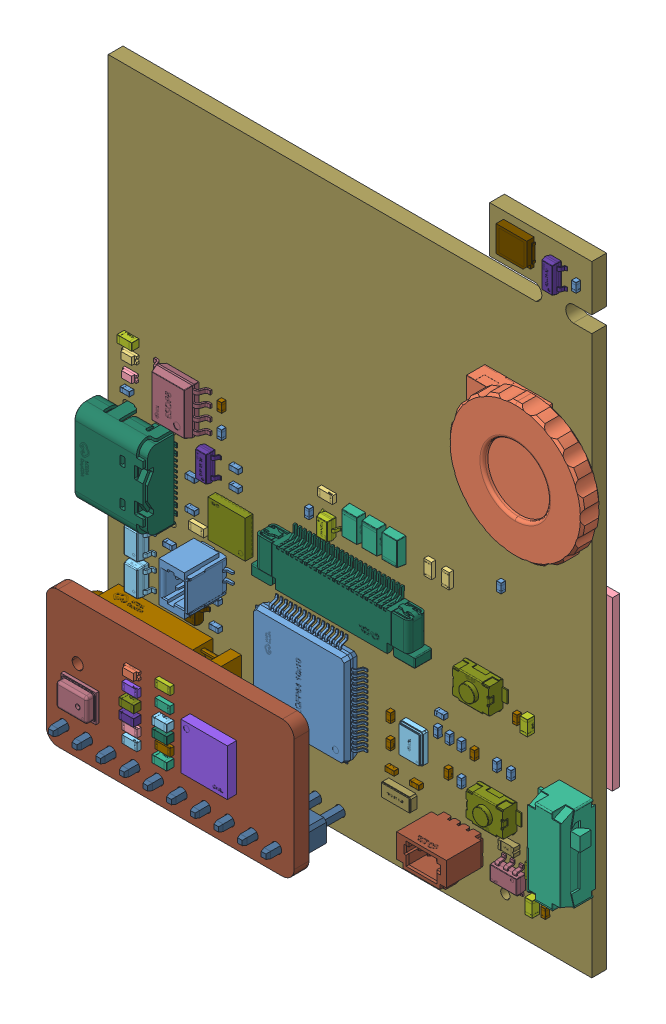
SolidWorks assembly acho_pcb, configuration 默认. Lengths in mm.
Overall size (56.46 68.19 13.11).
365 component instances, 66 part files, 0 mates.
Components (placement in the parent):
- acho_pcb.step-1: acho_pcb.step [默认] at origin size (55.33 67.76 13.11)
  - fs8s-R9.step-1: fs8s-R9.step [默认] at (9.271 25.4001 1.5862) size (1 0.5 0.5)
    - R0402.step-1: R0402.step [默认] at origin size (1 0.5 0.5)
      - SOLID.step-1: SOLID.step [默认] at origin size (1 0.5 0.5)
  - fs8s-R8.step-1: fs8s-R8.step [默认] at (9.271 22.352 1.5862) size (1 0.5 0.5)
    - R0402.step-1: R0402.step [默认] at origin size (1 0.5 0.5)
      - SOLID.step-1: SOLID.step [默认] at origin size (1 0.5 0.5)
  - fs8s-R3.step-1: fs8s-R3.step [默认] at (17.018 27.8131 0) x (-1 0 0) z (0 0 -1) size (1 0.5 0.5)
    - R0402.step-1: R0402.step [默认] at origin size (1 0.5 0.5)
      - SOLID.step-1: SOLID.step [默认] at origin size (1 0.5 0.5)
  - fs8s-R5.step-1: fs8s-R5.step [默认] at (21.463 27.8131 0) x (1 0 0) z (0 0 -1) size (1 0.5 0.5)
    - R0402.step-1: R0402.step [默认] at origin size (1 0.5 0.5)
      - SOLID.step-1: SOLID.step [默认] at origin size (1 0.5 0.5)
  - fs8s-R4.step-1: fs8s-R4.step [默认] at (19.304 27.8131 0) x (-1 0 0) z (0 0 -1) size (1 0.5 0.5)
    - R0402.step-1: R0402.step [默认] at origin size (1 0.5 0.5)
      - SOLID.step-1: SOLID.step [默认] at origin size (1 0.5 0.5)
  - fs8s-R13.step-1: fs8s-R13.step [默认] at (2.286 29.9721 1.5862) size (1 0.5 0.5)
    - R0402.step-1: R0402.step [默认] at origin size (1 0.5 0.5)
      - SOLID.step-1: SOLID.step [默认] at origin size (1 0.5 0.5)
  - fs8s-R16.step-1: fs8s-R16.step [默认] at (12.446 31.1151 1.5862) x (0 1 0) z (0 0 1) size (1 0.5 0.5)
    - R0402.step-1: R0402.step [默认] at origin size (1 0.5 0.5)
      - SOLID.step-1: SOLID.step [默认] at origin size (1 0.5 0.5)
  - fs8s-R28.step-1: fs8s-R28.step [默认] at (42.483 31.866 1.5862) x (0 -1 0) z (0 0 1) size (1 0.5 0.5)
    - R0402.step-1: R0402.step [默认] at origin size (1 0.5 0.5)
      - SOLID.step-1: SOLID.step [默认] at origin size (1 0.5 0.5)
  - fs8s-R26.step-1: fs8s-R26.step [默认] at (6.858 14.478 1.5862) x (-1 0 0) z (0 0 1) size (1 0.5 0.5)
    - R0402.step-1: R0402.step [默认] at origin size (1 0.5 0.5)
      - SOLID.step-1: SOLID.step [默认] at origin size (1 0.5 0.5)
  - fs8s-R31.step-1: fs8s-R31.step [默认] at (7.62 4.953 0) x (1 0 0) z (0 0 -1) size (1 0.5 0.5)
    - R0402.step-1: R0402.step [默认] at origin size (1 0.5 0.5)
      - SOLID.step-1: SOLID.step [默认] at origin size (1 0.5 0.5)
  - fs8s-R29.step-1: fs8s-R29.step [默认] at (11.43 9.652 0) x (0 1 0) z (0 0 -1) size (1 0.5 0.5)
    - R0402.step-1: R0402.step [默认] at origin size (1 0.5 0.5)
      - SOLID.step-1: SOLID.step [默认] at origin size (1 0.5 0.5)
  - fs8s-R32.step-1: fs8s-R32.step [默认] at (7.62 6.223 0) x (1 0 0) z (0 0 -1) size (1 0.5 0.5)
    - R0402.step-1: R0402.step [默认] at origin size (1 0.5 0.5)
      - SOLID.step-1: SOLID.step [默认] at origin size (1 0.5 0.5)
  - fs8s-R25.step-1: fs8s-R25.step [默认] at (6.858 17.907 1.5862) x (-1 0 0) z (0 0 1) size (1 0.5 0.5)
    - R0402.step-1: R0402.step [默认] at origin size (1 0.5 0.5)
      - SOLID.step-1: SOLID.step [默认] at origin size (1 0.5 0.5)
  - fs8s-R27.step-1: fs8s-R27.step [默认] at (6.858 12.827 1.5862) size (1 0.5 0.5)
    - R0402.step-1: R0402.step [默认] at origin size (1 0.5 0.5)
      - SOLID.step-1: SOLID.step [默认] at origin size (1 0.5 0.5)
  - fs8s-R7.step-1: fs8s-R7.step [默认] at (11.811 12.7 1.5862) x (-1 0 0) z (0 0 1) size (1 0.5 0.5)
    - R0402.step-1: R0402.step [默认] at origin size (1 0.5 0.5)
      - SOLID.step-1: SOLID.step [默认] at origin size (1 0.5 0.5)
  - fs8s-R10.step-1: fs8s-R10.step [默认] at (50.5461 63.8811 1.5862) x (0 1 0) z (0 0 1) size (1 0.5 0.5)
    - R0402.step-1: R0402.step [默认] at origin size (1 0.5 0.5)
      - SOLID.step-1: SOLID.step [默认] at origin size (1 0.5 0.5)
  - fs8s-R2.step-1: fs8s-R2.step [默认] at (38.2271 11.557 1.5862) x (0 1 0) z (0 0 1) size (1 0.5 0.5)
    - R0402.step-1: R0402.step [默认] at origin size (1 0.5 0.5)
      - SOLID.step-1: SOLID.step [默认] at origin size (1 0.5 0.5)
  - fs8s-R1.step-1: fs8s-R1.step [默认] at (24.257 10.795 0) x (0 1 0) z (0 0 -1) size (1 0.5 0.5)
    - R0402.step-1: R0402.step [默认] at origin size (1 0.5 0.5)
      - SOLID.step-1: SOLID.step [默认] at origin size (1 0.5 0.5)
  - fs8s-R30.step-1: fs8s-R30.step [默认] at (36.0681 16.764 1.5862) x (-1 0 0) z (0 0 1) size (1 0.5 0.5)
    - R0402.step-1: R0402.step [默认] at origin size (1 0.5 0.5)
      - SOLID.step-1: SOLID.step [默认] at origin size (1 0.5 0.5)
  - fs8s-R23.step-1: fs8s-R23.step [默认] at (21.844 28.4481 1.5862) x (0 1 0) z (0 0 1) size (1 0.5 0.5)
    - R0402.step-1: R0402.step [默认] at origin size (1 0.5 0.5)
      - SOLID.step-1: SOLID.step [默认] at origin size (1 0.5 0.5)
  - fs8s-R18.step-1: fs8s-R18.step [默认] at (43.5611 14.9627 1.5862) x (0 1 0) z (0 0 1) size (1 0.5 0.5)
    - R0402.step-1: R0402.step [默认] at origin size (1 0.5 0.5)
      - SOLID.step-1: SOLID.step [默认] at origin size (1 0.5 0.5)
  - fs8s-R22.step-1: fs8s-R22.step [默认] at (35.6871 14.986 1.5862) x (0 1 0) z (0 0 1) size (1 0.5 0.5)
    - R0402.step-1: R0402.step [默认] at origin size (1 0.5 0.5)
      - SOLID.step-1: SOLID.step [默认] at origin size (1 0.5 0.5)
  - fs8s-R19.step-1: fs8s-R19.step [默认] at (42.0371 14.986 1.5862) x (0 1 0) z (0 0 1) size (1 0.5 0.5)
    - R0402.step-1: R0402.step [默认] at origin size (1 0.5 0.5)
      - SOLID.step-1: SOLID.step [默认] at origin size (1 0.5 0.5)
  - fs8s-R20.step-1: fs8s-R20.step [默认] at (38.2271 14.986 1.5862) x (0 1 0) z (0 0 1) size (1 0.5 0.5)
    - R0402.step-1: R0402.step [默认] at origin size (1 0.5 0.5)
      - SOLID.step-1: SOLID.step [默认] at origin size (1 0.5 0.5)
  - fs8s-R21.step-1: fs8s-R21.step [默认] at (36.9571 14.986 1.5862) x (0 1 0) z (0 0 1) size (1 0.5 0.5)
    - R0402.step-1: R0402.step [默认] at origin size (1 0.5 0.5)
      - SOLID.step-1: SOLID.step [默认] at origin size (1 0.5 0.5)
  - fs8s-R6.step-1: fs8s-R6.step [默认] at (11.811 15.24 1.5862) size (1 0.5 0.5)
    - R0402.step-1: R0402.step [默认] at origin size (1 0.5 0.5)
      - SOLID.step-1: SOLID.step [默认] at origin size (1 0.5 0.5)
  - fs8s-R34.step-1: fs8s-R34.step [默认] at (43.9421 63.6271 0) x (-1 0 0) z (0 0 -1) size (1 0.5 0.5)
    - R0402.step-1: R0402.step [默认] at origin size (1 0.5 0.5)
      - SOLID.step-1: SOLID.step [默认] at origin size (1 0.5 0.5)
  - fs8s-R35.step-1: fs8s-R35.step [默认] at (13.97 26.7971 1.5862) x (-1 0 0) z (0 0 1) size (1 0.5 0.5)
    - R0402.step-1: R0402.step [默认] at origin size (1 0.5 0.5)
      - SOLID.step-1: SOLID.step [默认] at origin size (1 0.5 0.5)
  - fs8s-R36.step-1: fs8s-R36.step [默认] at (13.97 28.5751 1.5862) x (-1 0 0) z (0 0 1) size (1 0.5 0.5)
    - R0402.step-1: R0402.step [默认] at origin size (1 0.5 0.5)
      - SOLID.step-1: SOLID.step [默认] at origin size (1 0.5 0.5)
  - fs8s-R24.step-1: fs8s-R24.step [默认] at (6.858 16.129 1.5862) x (-1 0 0) z (0 0 1) size (1 0.5 0.5)
    - R0402.step-1: R0402.step [默认] at origin size (1 0.5 0.5)
      - SOLID.step-1: SOLID.step [默认] at origin size (1 0.5 0.5)
  - fs8s-U3.step-1: fs8s-U3.step [默认] at (19 32.0001 0) x (1 0 0) z (0 0 -1) size (4.9 6 1.55)
    - SO-8_L4.9-W3.9-P1.27-LS6.0-BL.step-1: SO-8_L4.9-W3.9-P1.27-LS6.0-BL.step [默认] at origin size (4.9 6 1.55)
      - SOLID-0.step-1: SOLID-0.step [默认] at origin size (4.9 6 1.55)
  - fs8s-LED2.step-1: fs8s-LED2.step [默认] at (2.54 33.2741 1.5862) x (-1 0 0) z (0 0 1) size (1.6 0.8 0.6)
    - LED_0603.step-1: LED_0603.step [默认] at origin size (1.6 0.8 0.6)
      - COMPOUND.step-1: COMPOUND.step [默认] at origin size (1.6 0.8 0.6)
  - fs8s-LED3.step-1: fs8s-LED3.step [默认] at (2.54 31.4961 1.5862) x (-1 0 0) z (0 0 1) size (1.49 0.75 0.56)
    - LED_0603-1.step-1: LED_0603-1.step [默认] at origin size (1.49 0.75 0.56)
      - COMPOUND-1.step-1: COMPOUND-1.step [默认] at origin size (1.49 0.75 0.56)
  - fs8s-U12.step-1: fs8s-U12.step [默认] at (3.7611 13.589 1.5862) size (2.8 2.9 1.4)
    - SOT-23-3_L2.9-W1.6-P1.90-LS2.8-BR.step-1: SOT-23-3_L2.9-W1.6-P1.90-LS2.8-BR.step [默认] at origin size (2.8 2.9 1.4)
      - SOLID-2.step-1: SOLID-2.step [默认] at origin size (2.8 2.9 1.4)
  - fs8s-U11.step-1: fs8s-U11.step [默认] at (3.7611 17.018 1.5862) size (2.8 2.9 1.4)
    - SOT-23-3_L2.9-W1.6-P1.90-LS2.8-BR.step-1: SOT-23-3_L2.9-W1.6-P1.90-LS2.8-BR.step [默认] at origin size (2.8 2.9 1.4)
      - SOLID-2.step-1: SOLID-2.step [默认] at origin size (2.8 2.9 1.4)
  - fs8s-SW1.step-1: fs8s-SW1.step [默认] at (47.4981 12.319 1.5862) x (0 -1 0) z (0 0 1) size (9.23 6.61 4.33)
    - eBom-asm42.step-1: eBom-asm42.step [默认] at origin size (9.23 6.61 4.33)
      - COMPOUND-3.step-1: COMPOUND-3.step [默认] at origin size (9.23 6.61 4.33)
  - fs8s-C37.step-1: fs8s-C37.step [默认] at (45.4661 20.574 1.5862) x (0 -1 0) z (0 0 1) size (1.6 0.8 0.8)
    - C0603.step-1: C0603.step [默认] at origin size (1.6 0.8 0.8)
      - SOLID-4.step-1: SOLID-4.step [默认] at origin size (1.6 0.8 0.8)
  - fs8s-C26.step-1: fs8s-C26.step [默认] at (45.9741 7.239 1.5862) x (0 -1 0) z (0 0 1) size (1.6 0.8 0.8)
    - C0603.step-1: C0603.step [默认] at origin size (1.6 0.8 0.8)
      - SOLID-4.step-1: SOLID-4.step [默认] at origin size (1.6 0.8 0.8)
  - fs8s-C18.step-1: fs8s-C18.step [默认] at (2.54 34.7981 1.5862) size (1.6 0.8 0.8)
    - C0603.step-1: C0603.step [默认] at origin size (1.6 0.8 0.8)
      - SOLID-4.step-1: SOLID-4.step [默认] at origin size (1.6 0.8 0.8)
  - fs8s-C36.step-1: fs8s-C36.step [默认] at (2.54 9.144 0) x (0 -1 0) z (0 0 -1) size (1.6 0.8 0.8)
    - C0603-1.step-1: C0603-1.step [默认] at origin size (1.6 0.8 0.8)
      - SOLID-5.step-1: SOLID-5.step [默认] at origin size (1.6 0.8 0.8)
  - fs8s-C34.step-1: fs8s-C34.step [默认] at (4.318 9.144 0) x (0 -1 0) z (0 0 -1) size (1.6 0.8 0.8)
    - C0603-1.step-1: C0603-1.step [默认] at origin size (1.6 0.8 0.8)
      - SOLID-5.step-1: SOLID-5.step [默认] at origin size (1.6 0.8 0.8)
  - fs8s-C29.step-1: fs8s-C29.step [默认] at (45.9741 3.937 1.5862) x (0 1 0) z (0 0 1) size (1.6 0.8 0.8)
    - C0603.step-1: C0603.step [默认] at origin size (1.6 0.8 0.8)
      - SOLID-4.step-1: SOLID-4.step [默认] at origin size (1.6 0.8 0.8)
  - fs8s-C20.step-1: fs8s-C20.step [默认] at (26.1621 28.8291 0) x (-1 0 0) z (0 0 -1) size (1.6 0.8 0.8)
    - C0603.step-1: C0603.step [默认] at origin size (1.6 0.8 0.8)
      - SOLID-4.step-1: SOLID-4.step [默认] at origin size (1.6 0.8 0.8)
  - fs8s-C22.step-1: fs8s-C22.step [默认] at (29.5911 28.8291 0) x (-1 0 0) z (0 0 -1) size (1.6 0.8 0.8)
    - C0603.step-1: C0603.step [默认] at origin size (1.6 0.8 0.8)
      - SOLID-4.step-1: SOLID-4.step [默认] at origin size (1.6 0.8 0.8)
  - fs8s-C8.step-1: fs8s-C8.step [默认] at (15.621 33.4011 0) x (0 1 0) z (0 0 -1) size (1.6 0.8 0.8)
    - C0603.step-1: C0603.step [默认] at origin size (1.6 0.8 0.8)
      - SOLID-4.step-1: SOLID-4.step [默认] at origin size (1.6 0.8 0.8)
  - fs8s-C19.step-1: fs8s-C19.step [默认] at (39.6241 14.859 1.5862) x (0 1 0) z (0 0 1) size (1 0.5 0.5)
    - C0402.step-1: C0402.step [默认] at origin size (1 0.5 0.5)
      - SOLID-6.step-1: SOLID-6.step [默认] at origin size (1 0.5 0.5)
  - fs8s-C28.step-1: fs8s-C28.step [默认] at (47.2441 3.937 1.5862) x (0 1 0) z (0 0 1) size (1 0.5 0.5)
    - C0402.step-1: C0402.step [默认] at origin size (1 0.5 0.5)
      - SOLID-6.step-1: SOLID-6.step [默认] at origin size (1 0.5 0.5)
  - fs8s-C27.step-1: fs8s-C27.step [默认] at (47.2441 7.239 1.5862) x (0 -1 0) z (0 0 1) size (1 0.5 0.5)
    - C0402.step-1: C0402.step [默认] at origin size (1 0.5 0.5)
      - SOLID-6.step-1: SOLID-6.step [默认] at origin size (1 0.5 0.5)
  - fs8s-C17.step-1: fs8s-C17.step [默认] at (12.446 33.6551 1.5862) x (0 1 0) z (0 0 1) size (1 0.5 0.5)
    - C0402.step-1: C0402.step [默认] at origin size (1 0.5 0.5)
      - SOLID-6.step-1: SOLID-6.step [默认] at origin size (1 0.5 0.5)
  - fs8s-C5.step-1: fs8s-C5.step [默认] at (36.8301 11.684 1.5862) x (0 -1 0) z (0 0 1) size (1 0.5 0.5)
    - C0402.step-1: C0402.step [默认] at origin size (1 0.5 0.5)
      - SOLID-6.step-1: SOLID-6.step [默认] at origin size (1 0.5 0.5)
  - fs8s-C32.step-1: fs8s-C32.step [默认] at (31.4961 25.9081 0) x (0 1 0) z (0 0 -1) size (1 0.5 0.5)
    - C0402.step-1: C0402.step [默认] at origin size (1 0.5 0.5)
      - SOLID-6.step-1: SOLID-6.step [默认] at origin size (1 0.5 0.5)
  - fs8s-C31.step-1: fs8s-C31.step [默认] at (30.2289 23.114 0) x (0 1 0) z (0 0 -1) size (1 0.5 0.5)
    - C0402.step-1: C0402.step [默认] at origin size (1 0.5 0.5)
      - SOLID-6.step-1: SOLID-6.step [默认] at origin size (1 0.5 0.5)
  - fs8s-C25.step-1: fs8s-C25.step [默认] at (28.9589 23.114 0) x (0 1 0) z (0 0 -1) size (1 0.5 0.5)
    - C0402.step-1: C0402.step [默认] at origin size (1 0.5 0.5)
      - SOLID-6.step-1: SOLID-6.step [默认] at origin size (1 0.5 0.5)
  - fs8s-C21.step-1: fs8s-C21.step [默认] at (27.6861 25.9081 0) x (0 1 0) z (0 0 -1) size (1 0.5 0.5)
    - C0402.step-1: C0402.step [默认] at origin size (1 0.5 0.5)
      - SOLID-6.step-1: SOLID-6.step [默认] at origin size (1 0.5 0.5)
  - fs8s-C23.step-1: fs8s-C23.step [默认] at (27.6861 23.114 0) x (0 1 0) z (0 0 -1) size (1 0.5 0.5)
    - C0402.step-1: C0402.step [默认] at origin size (1 0.5 0.5)
      - SOLID-6.step-1: SOLID-6.step [默认] at origin size (1 0.5 0.5)
  - fs8s-C24.step-1: fs8s-C24.step [默认] at (28.9561 25.9081 0) x (0 1 0) z (0 0 -1) size (1 0.5 0.5)
    - C0402.step-1: C0402.step [默认] at origin size (1 0.5 0.5)
      - SOLID-6.step-1: SOLID-6.step [默认] at origin size (1 0.5 0.5)
  - fs8s-C11.step-1: fs8s-C11.step [默认] at (25.1461 16.51 0) x (-1 0 0) z (0 0 -1) size (1 0.5 0.5)
    - C0402.step-1: C0402.step [默认] at origin size (1 0.5 0.5)
      - SOLID-6.step-1: SOLID-6.step [默认] at origin size (1 0.5 0.5)
  - fs8s-C12.step-1: fs8s-C12.step [默认] at (19.177 15.748 0) x (-1 0 0) z (0 0 -1) size (1 0.5 0.5)
    - C0402.step-1: C0402.step [默认] at origin size (1 0.5 0.5)
      - SOLID-6.step-1: SOLID-6.step [默认] at origin size (1 0.5 0.5)
  - fs8s-C14.step-1: fs8s-C14.step [默认] at (24.765 9.017 0) x (1 0 0) z (0 0 -1) size (1 0.5 0.5)
    - C0402.step-1: C0402.step [默认] at origin size (1 0.5 0.5)
      - SOLID-6.step-1: SOLID-6.step [默认] at origin size (1 0.5 0.5)
  - fs8s-C13.step-1: fs8s-C13.step [默认] at (19.177 9.144 0) x (-1 0 0) z (0 0 -1) size (1 0.5 0.5)
    - C0402.step-1: C0402.step [默认] at origin size (1 0.5 0.5)
      - SOLID-6.step-1: SOLID-6.step [默认] at origin size (1 0.5 0.5)
  - fs8s-C10.step-1: fs8s-C10.step [默认] at (25.1461 15.113 0) x (1 0 0) z (0 0 -1) size (1 0.5 0.5)
    - C0402.step-1: C0402.step [默认] at origin size (1 0.5 0.5)
      - SOLID-6.step-1: SOLID-6.step [默认] at origin size (1 0.5 0.5)
  - fs8s-C35.step-1: fs8s-C35.step [默认] at (44.1961 20.447 1.5862) x (0 -1 0) z (0 0 1) size (1 0.5 0.5)
    - C0402.step-1: C0402.step [默认] at origin size (1 0.5 0.5)
      - SOLID-6.step-1: SOLID-6.step [默认] at origin size (1 0.5 0.5)
  - fs8s-C33.step-1: fs8s-C33.step [默认] at (31.4961 23.114 0) x (0 1 0) z (0 0 -1) size (1 0.5 0.5)
    - C0402.step-1: C0402.step [默认] at origin size (1 0.5 0.5)
      - SOLID-6.step-1: SOLID-6.step [默认] at origin size (1 0.5 0.5)
  - fs8s-C9.step-1: fs8s-C9.step [默认] at (19.177 14.351 0) x (-1 0 0) z (0 0 -1) size (1 0.5 0.5)
    - C0402.step-1: C0402.step [默认] at origin size (1 0.5 0.5)
      - SOLID-6.step-1: SOLID-6.step [默认] at origin size (1 0.5 0.5)
  - fs8s-C30.step-1: fs8s-C30.step [默认] at (30.2261 25.9081 0) x (0 1 0) z (0 0 -1) size (1 0.5 0.5)
    - C0402.step-1: C0402.step [默认] at origin size (1 0.5 0.5)
      - SOLID-6.step-1: SOLID-6.step [默认] at origin size (1 0.5 0.5)
  - fs8s-C16.step-1: fs8s-C16.step [默认] at (23.368 23.114 0) x (0 1 0) z (0 0 -1) size (1 0.5 0.5)
    - C0402.step-1: C0402.step [默认] at origin size (1 0.5 0.5)
      - SOLID-6.step-1: SOLID-6.step [默认] at origin size (1 0.5 0.5)
  - fs8s-C15.step-1: fs8s-C15.step [默认] at (22.098 23.114 0) x (0 1 0) z (0 0 -1) size (1 0.5 0.5)
    - C0402.step-1: C0402.step [默认] at origin size (1 0.5 0.5)
      - SOLID-6.step-1: SOLID-6.step [默认] at origin size (1 0.5 0.5)
  - fs8s-C1.step-1: fs8s-C1.step [默认] at (25.5271 10.922 0) x (0 -1 0) z (0 0 -1) size (1 0.5 0.5)
    - C0402.step-1: C0402.step [默认] at origin size (1 0.5 0.5)
      - SOLID-6.step-1: SOLID-6.step [默认] at origin size (1 0.5 0.5)
  - fs8s-C7.step-1: fs8s-C7.step [默认] at (30.6071 11.303 1.5862) x (0 -1 0) z (0 0 1) size (1 0.5 0.5)
    - C0402.step-1: C0402.step [默认] at origin size (1 0.5 0.5)
      - SOLID-6.step-1: SOLID-6.step [默认] at origin size (1 0.5 0.5)
  - fs8s-C4.step-1: fs8s-C4.step [默认] at (30.6071 13.843 1.5862) x (0 1 0) z (0 0 1) size (1 0.5 0.5)
    - C0402.step-1: C0402.step [默认] at origin size (1 0.5 0.5)
      - SOLID-6.step-1: SOLID-6.step [默认] at origin size (1 0.5 0.5)
  - fs8s-C3.step-1: fs8s-C3.step [默认] at (30.7341 8.89 1.5862) size (1 0.5 0.5)
    - C0402.step-1: C0402.step [默认] at origin size (1 0.5 0.5)
      - SOLID-6.step-1: SOLID-6.step [默认] at origin size (1 0.5 0.5)
  - fs8s-C2.step-1: fs8s-C2.step [默认] at (33.4011 8.89 1.5862) x (-1 0 0) z (0 0 1) size (1 0.5 0.5)
    - C0402.step-1: C0402.step [默认] at origin size (1 0.5 0.5)
      - SOLID-6.step-1: SOLID-6.step [默认] at origin size (1 0.5 0.5)
  - fs8s-C38.step-1: fs8s-C38.step [默认] at (13.97 26.4161 0) x (0 -1 0) z (0 0 -1) size (1 0.5 0.5)
    - C0402.step-1: C0402.step [默认] at origin size (1 0.5 0.5)
      - SOLID-6.step-1: SOLID-6.step [默认] at origin size (1 0.5 0.5)
  - fs8s-C6.step-1: fs8s-C6.step [默认] at (15.621 30.4059 0) x (0 -1 0) z (0 0 -1) size (1 0.5 0.5)
    - C0402.step-1: C0402.step [默认] at origin size (1 0.5 0.5)
      - SOLID-6.step-1: SOLID-6.step [默认] at origin size (1 0.5 0.5)
  - fs8s-D6.step-1: fs8s-D6.step [默认] at (4.191 6.35 0) x (1 0 0) z (0 0 -1) size (3.68 1.6 1.22)
    - SOD-123_L2.8-W1.8-LS3.7-RD.step-1: SOD-123_L2.8-W1.8-LS3.7-RD.step [默认] at origin size (3.68 1.6 1.22)
      - SOLID-7.step-1: SOLID-7.step [默认] at origin size (3.68 1.6 1.22)
  - fs8s-D2.step-1: fs8s-D2.step [默认] at (4.953 13.716 0) x (1 0 0) z (0 0 -1) size (4.7 2.6 2.1)
    - SMA_L4.3-W2.6-LS5.2-RD.step-1: SMA_L4.3-W2.6-LS5.2-RD.step [默认] at origin size (4.7 2.6 2.1)
      - COMPOUND-8.step-1: COMPOUND-8.step [默认] at origin size (4.7 2.6 2.1)
  - fs8s-D1.step-1: fs8s-D1.step [默认] at (4.953 17.272 0) x (1 0 0) z (0 0 -1) size (4.7 2.6 2.1)
    - SMA_L4.3-W2.6-LS5.2-RD.step-1: SMA_L4.3-W2.6-LS5.2-RD.step [默认] at origin size (4.7 2.6 2.1)
      - COMPOUND-8.step-1: COMPOUND-8.step [默认] at origin size (4.7 2.6 2.1)
  - fs8s-U13.step-1: fs8s-U13.step [默认] at (43.4341 8.128 1.5862) x (-1 0 0) z (0 0 1) size (1.7 0.9 0.7)
    - F0603.step-1: F0603.step [默认] at origin size (1.7 0.9 0.7)
      - SOLID-9.step-1: SOLID-9.step [默认] at origin size (1.7 0.9 0.7)
  - fs8s-U14.step-1: fs8s-U14.step [默认] at (43.5611 5.461 1.5862) x (0 1 0) z (0 0 1) size (2.9 2.9 1.1)
    - SOT-23-5_L2.9-W1.6-P0.95-LS2.8-BR.step-1: SOT-23-5_L2.9-W1.6-P0.95-LS2.8-BR.step [默认] at origin size (2.9 2.9 1.1)
      - COMPOUND-10.step-1: COMPOUND-10.step [默认] at origin size (2.9 2.9 1.1)
  - fs8s-U17.step-1: fs8s-U17.step [默认] at (8.89 9.144 0) x (0 -1 0) z (0 0 -1) size (2.8 2.9 1.25)
    - SOT-23-6_L2.9-W1.6-P0.95-LS2.8-BR.step-1: SOT-23-6_L2.9-W1.6-P0.95-LS2.8-BR.step [默认] at origin size (2.8 2.9 1.25)
      - SOLID-11.step-1: SOLID-11.step [默认] at origin size (2.8 2.9 1.25)
  - fs8s-USB1.step-1: fs8s-USB1.step [默认] at (4.699 24.13 1.5862) x (0 -1 0) z (0 0 1) size (8.95 7.81 4.35)
    - USB-C-SMD_KH-TYPE-C-16P.step-1: USB-C-SMD_KH-TYPE-C-16P.step [默认] at origin size (8.95 7.81 4.35)
      - COMPOUND-12.step-1: COMPOUND-12.step [默认] at origin size (8.95 7.81 4.35)
  - fs8s-U18.step-1: fs8s-U18.step [默认] at (40.5131 21.717 1.5862) x (-1 0 0) z (0 0 1) size (5 2.95 2)
    - KEY-SMD_L3.9-W3.0-LS5.0.step-1: KEY-SMD_L3.9-W3.0-LS5.0.step [默认] at origin size (5 2.95 2)
      - SOLID-13.step-1: SOLID-13.step [默认] at origin size (5 2.95 2)
  - fs8s-U2.step-1: fs8s-U2.step [默认] at (42.0001 11 1.5862) size (5 2.95 2)
    - KEY-SMD_L3.9-W3.0-LS5.0.step-1: KEY-SMD_L3.9-W3.0-LS5.0.step [默认] at origin size (5 2.95 2)
      - SOLID-13.step-1: SOLID-13.step [默认] at origin size (5 2.95 2)
  - fs8s-U10.step-1: fs8s-U10.step [默认] at (37.8461 8.89 0) x (-1 0 0) z (0 0 -1) size (16.15 15.25 2.65)
    - SIM-SMD_C9900015645.step-1: SIM-SMD_C9900015645.step [默认] at origin size (16.15 15.25 2.65)
      - COMPOUND-14.step-1: COMPOUND-14.step [默认] at origin size (16.15 15.25 2.65)
  - fs8s-LED1.step-1: fs8s-LED1.step [默认] at (43.8151 64.5161 1.5862) size (3.5 2.81 0.82)
    - LED-SMD_L3.5-W2.8_28353V60MA6500K.step-1: LED-SMD_L3.5-W2.8_28353V60MA6500K.step [默认] at origin size (3.5 2.81 0.82)
      - COMPOUND-15.step-1: COMPOUND-15.step [默认] at origin size (3.5 2.81 0.82)
  - fs8s-CN1.step-1: fs8s-CN1.step [默认] at (12.0904 18.0594 1.5862) x (0 -1 0) z (0 0 1) size (4.33 3.74 4.4)
    - CONN-SMD_2P-P1.00_HC-1.0-2PLT.step-1: CONN-SMD_2P-P1.00_HC-1.0-2PLT.step [默认] at origin size (4.33 3.74 4.4)
      - SOLID-16.step-1: SOLID-16.step [默认] at origin size (4.33 3.74 4.4)
  - fs8s-U9.step-1: fs8s-U9.step [默认] at (45.3391 46.2281 1.5862) x (0 -1 0) z (0 0 1) size (14.5 14.47 4.5)
    - SW-SMD_SIQ-02FVS3_1.step-1: SW-SMD_SIQ-02FVS3_1.step [默认] at origin size (14.5 14.47 4.5)
      - COMPOUND-17.step-1: COMPOUND-17.step [默认] at origin size (14.5 14.47 4.5)
  - fs8s-R14.step-1: fs8s-R14.step [默认] at (36.7031 29.7181 1.5862) x (0 -1 0) z (0 0 1) size (1.62 0.81 0.45)
    - R0603.step-1: R0603.step [默认] at origin size (1.62 0.81 0.45)
      - COMPOUND-18.step-1: COMPOUND-18.step [默认] at origin size (1.62 0.81 0.45)
  - fs8s-R11.step-1: fs8s-R11.step [默认] at (9.906 20.955 1.5862) size (1.62 0.81 0.45)
    - R0603.step-1: R0603.step [默认] at origin size (1.62 0.81 0.45)
      - COMPOUND-18.step-1: COMPOUND-18.step [默认] at origin size (1.62 0.81 0.45)
  - fs8s-R17.step-1: fs8s-R17.step [默认] at (23.749 30.9881 1.5862) x (-1 0 0) z (0 0 1) size (1.62 0.81 0.45)
    - R0603.step-1: R0603.step [默认] at origin size (1.62 0.81 0.45)
      - COMPOUND-18.step-1: COMPOUND-18.step [默认] at origin size (1.62 0.81 0.45)
  - fs8s-R33.step-1: fs8s-R33.step [默认] at (44.1961 65.2781 0) x (1 0 0) z (0 0 -1) size (1.62 0.81 0.45)
    - R0603.step-1: R0603.step [默认] at origin size (1.62 0.81 0.45)
      - COMPOUND-18.step-1: COMPOUND-18.step [默认] at origin size (1.62 0.81 0.45)
  - fs8s-R15.step-1: fs8s-R15.step [默认] at (34.7981 29.7181 1.5862) x (0 -1 0) z (0 0 1) size (1.62 0.81 0.45)
    - R0603.step-1: R0603.step [默认] at origin size (1.62 0.81 0.45)
      - COMPOUND-18.step-1: COMPOUND-18.step [默认] at origin size (1.62 0.81 0.45)
  - fs8s-U16.step-1: fs8s-U16.step [默认] at (39.4971 25.9081 0) x (0 1 0) z (0 0 -1) size (18.02 20 3.22)
    - BULETM-SMD_ESPRESSIF_ESP32-C3-WROOM-02-N4-4MB.step-1: BULETM-SMD_ESPRESSIF_ESP32-C3-WROOM-02-N4-4MB.step [默认] at origin size (18.02 20 3.22)
      - SOLID-19.step-1: SOLID-19.step [默认] at origin size (18.02 20 3.22)
  - fs8s-X2.step-1: fs8s-X2.step [默认] at (33.1471 12.7 1.5862) x (0 1 0) z (0 0 1) size (3.2 2.5 0.81)
    - OSC-SMD_4P-L3.2-W2.5-BL.step-1: OSC-SMD_4P-L3.2-W2.5-BL.step [默认] at origin size (3.2 2.5 0.81)
      - SOLID-20.step-1: SOLID-20.step [默认] at origin size (3.2 2.5 0.81)
  - fs8s-D4.step-1: fs8s-D4.step [默认] at (31.1151 29.8451 1.5862) x (0 -1 0) z (0 0 1) size (3.7 1.8 1.14)
    - SOD-123FL_L2.7-W1.8-LS3.7-RD.step-1: SOD-123FL_L2.7-W1.8-LS3.7-RD.step [默认] at origin size (3.7 1.8 1.14)
      - SOLID-21.step-1: SOLID-21.step [默认] at origin size (3.7 1.8 1.14)
  - fs8s-D3.step-1: fs8s-D3.step [默认] at (26.7971 29.8451 1.5862) x (0 1 0) z (0 0 1) size (3.7 1.8 1.14)
    - SOD-123FL_L2.7-W1.8-LS3.7-RD.step-1: SOD-123FL_L2.7-W1.8-LS3.7-RD.step [默认] at origin size (3.7 1.8 1.14)
      - SOLID-21.step-1: SOLID-21.step [默认] at origin size (3.7 1.8 1.14)
  - fs8s-D5.step-1: fs8s-D5.step [默认] at (28.9561 29.8451 1.5862) x (0 1 0) z (0 0 1) size (3.7 1.8 1.14)
    - SOD-123FL_L2.7-W1.8-LS3.7-RD.step-1: SOD-123FL_L2.7-W1.8-LS3.7-RD.step [默认] at origin size (3.7 1.8 1.14)
      - SOLID-21.step-1: SOLID-21.step [默认] at origin size (3.7 1.8 1.14)
  - fs8s-Q3.step-1: fs8s-Q3.step [默认] at (24.13 28.4481 1.5862) x (-1 0 0) z (0 0 1) size (2.1 2 1.18)
    - SOT-323_L2.0-W1.3-P1.30-LS2.1-BR.step-1: SOT-323_L2.0-W1.3-P1.30-LS2.1-BR.step [默认] at origin size (2.1 2 1.18)
      - COMPOUND-22.step-1: COMPOUND-22.step [默认] at origin size (2.1 2 1.18)
  - fs8s-BUZZER1.step-1: fs8s-BUZZER1.step [默认] at (11.684 30.4801 0) x (-1 0 0) z (0 0 -1) size (5.2 5.28 2.01)
    - BUZ-SMD_L5.0-W5.5-P4.60.step-1: BUZ-SMD_L5.0-W5.5-P4.60.step [默认] at origin size (5.2 5.28 2.01)
      - SOLID-23.step-1: SOLID-23.step [默认] at origin size (5.2 5.28 2.01)
  - fs8s-U19.step-1: fs8s-U19.step [默认] at (11.049 26.5431 0) x (-1 0 0) z (0 0 -1) size (3.7 1.65 1.1)
    - SOD-123_L2.7-W1.7-LS3.8-RD.step-1: SOD-123_L2.7-W1.7-LS3.8-RD.step [默认] at origin size (3.7 1.65 1.1)
      - SOLID-24.step-1: SOLID-24.step [默认] at origin size (3.7 1.65 1.1)
  - fs8s-L2.step-1: fs8s-L2.step [默认] at (6.096 9.144 0) x (0 -1 0) z (0 0 -1) size (1.6 1.02 0.82)
    - IND-SMD_L1.6-W1.0.step-1: IND-SMD_L1.6-W1.0.step [默认] at origin size (1.6 1.02 0.82)
      - COMPOUND-25.step-1: COMPOUND-25.step [默认] at origin size (1.6 1.02 0.82)
  - fs8s-U5.step-1: fs8s-U5.step [默认] at (38.1001 5.334 1.5862) size (5.35 3.75 4.42)
    - CONN-SMD_3P-P1.00_BX-SH1.0-3PLT.step-1: CONN-SMD_3P-P1.00_BX-SH1.0-3PLT.step [默认] at origin size (5.35 3.75 4.42)
      - COMPOUND-26.step-1: COMPOUND-26.step [默认] at origin size (5.35 3.75 4.42)
  - fs8s-X1.step-1: fs8s-X1.step [默认] at (31.6231 6.985 1.5862) size (3.2 1.5 0.76)
    - OSC-SMD_L3.2-W1.5.step-1: OSC-SMD_L3.2-W1.5.step [默认] at origin size (3.2 1.5 0.76)
      - COMPOUND-27.step-1: COMPOUND-27.step [默认] at origin size (3.2 1.5 0.76)
  - fs8s-U7.step-1: fs8s-U7.step [默认] at (8.128 32.2581 1.5862) x (0 1 0) z (0 0 1) size (4.9 6.1 1.7)
    - ESOP-8_L4.9-W3.9-P1.27-LS6.0-BL-EP.step-1: ESOP-8_L4.9-W3.9-P1.27-LS6.0-BL-EP.step [默认] at origin size (4.9 6.1 1.7)
      - COMPOUND-28.step-1: COMPOUND-28.step [默认] at origin size (4.9 6.1 1.7)
  - fs8s-L1.step-1: fs8s-L1.step [默认] at (27.8131 32.2581 0) x (-1 0 0) z (0 0 -1) size (5.02 5 2.12)
    - IND-SMD_L5.0-W5.0.step-1: IND-SMD_L5.0-W5.0.step [默认] at origin size (5.02 5 2.12)
      - SOLID-29.step-1: SOLID-29.step [默认] at origin size (5.02 5 2.12)
  - fs8s-U8.step-1: fs8s-U8.step [默认] at (26.0001 25.0001 1.5862) size (17.6 5.4 2.01)
    - FPC-SMD_F0501-T-24-20T-R.step-1: FPC-SMD_F0501-T-24-20T-R.step [默认] at origin size (17.6 5.4 2.01)
      - COMPOUND-30.step-1: COMPOUND-30.step [默认] at origin size (17.6 5.4 2.01)
  - fs8s-U4.step-1: fs8s-U4.step [默认] at (13.589 23.027 1.5862) x (0 1 0) z (0 0 1) size (4 4 0.86)
    - QFN-28_L4.0-W4.0-P0.40-BL-EP.step-1: QFN-28_L4.0-W4.0-P0.40-BL-EP.step [默认] at origin size (4 4 0.86)
      - COMPOUND-31.step-1: COMPOUND-31.step [默认] at origin size (4 4 0.86)
  - fs8s-Q2.step-1: fs8s-Q2.step [默认] at (48.1331 63.7541 1.5862) size (2.5 2.9 1.05)
    - S8050_SOT-23.step-1: S8050_SOT-23.step [默认] at origin size (2.5 2.9 1.05)
      - COMPOUND-32.step-1: COMPOUND-32.step [默认] at origin size (2.5 2.9 1.05)
  - fs8s-Q4.step-1: fs8s-Q4.step [默认] at (10.922 27.5591 1.5862) size (2.5 2.9 1.05)
    - S8050_SOT-23.step-1: S8050_SOT-23.step [默认] at origin size (2.5 2.9 1.05)
      - COMPOUND-32.step-1: COMPOUND-32.step [默认] at origin size (2.5 2.9 1.05)
  - fs8s-Q1.step-1: fs8s-Q1.step [默认] at (9.779 13.843 1.5862) x (-1 0 0) z (0 0 1) size (2.5 2.89 1.05)
    - SOT-23-3_L2.9-W1.3-P1.90-LS2.4-BR.step-1: SOT-23-3_L2.9-W1.3-P1.90-LS2.4-BR.step [默认] at origin size (2.5 2.89 1.05)
      - COMPOUND-33.step-1: COMPOUND-33.step [默认] at origin size (2.5 2.89 1.05)
  - fs8s-U1.step-1: fs8s-U1.step [默认] at (21.944 12.873 1.5862) x (0 1 0) z (0 0 1) size (12 12 1.45)
    - LQFP-64_L10.0-W10.0-P0.50-LS12.0-BL.step-1: LQFP-64_L10.0-W10.0-P0.50-LS12.0-BL.step [默认] at origin size (12 12 1.45)
      - COMPOUND-34.step-1: COMPOUND-34.step [默认] at origin size (12 12 1.45)
  - fs8s-U15.step-1: fs8s-U15.step [默认] at (8.3058 1.27 1.5862) size (26.77 14.64 11.5)
    - Acho.step-1: Acho.step [默认] at origin size (26.77 14.64 11.5)
      - COMPOUND-35.step-1: COMPOUND-35.step [默认] at origin size (1.6 0.8 0.6)
      - COMPOUND-36.step-1: COMPOUND-36.step [默认] at origin size (1.62 0.81 0.45)
      - COMPOUND-37.step-1: COMPOUND-37.step [默认] at origin size (1.62 0.81 0.45)
      - COMPOUND-38.step-1: COMPOUND-38.step [默认] at origin size (1.62 0.81 0.45)
      - COMPOUND-39.step-1: COMPOUND-39.step [默认] at origin size (1.62 0.81 0.45)
      - COMPOUND-40.step-1: COMPOUND-40.step [默认] at origin size (1.62 0.81 0.45)
      - COMPOUND-41.step-1: COMPOUND-41.step [默认] at origin size (1.62 0.81 0.45)
      - COMPOUND-42.step-1: COMPOUND-42.step [默认] at origin size (1.62 0.81 0.45)
      - COMPOUND-43.step-1: COMPOUND-43.step [默认] at origin size (1.62 0.81 0.45)
      - COMPOUND-44.step-1: COMPOUND-44.step [默认] at origin size (1.62 0.81 0.45)
      - COMPOUND-45.step-1: COMPOUND-45.step [默认] at origin size (1.62 0.81 0.45)
      - COMPOUND-46.step-1: COMPOUND-46.step [默认] at origin size (3.76 2.95 1.11)
      - SOLID-47.step-1: SOLID-47.step [默认] at origin size (0.8 1.6 0.8)
      - SOLID-48.step-1: SOLID-48.step [默认] at origin size (1.6 0.8 0.8)
      - SOLID-49.step-1: SOLID-49.step [默认] at origin size (1.6 0.8 0.8)
      - SOLID-50.step-1: SOLID-50.step [默认] at origin size (1.6 0.8 0.8)
      - SOLID-51.step-1: SOLID-51.step [默认] at origin size (1.6 0.8 0.8)
      - SOLID-52.step-1: SOLID-52.step [默认] at origin size (1.6 0.8 0.8)
      - SOLID-53.step-1: SOLID-53.step [默认] at origin size (1.6 0.8 0.8)
      - SOLID-54.step-1: SOLID-54.step [默认] at origin size (1.6 0.8 0.8)
      - SOLID-55.step-1: SOLID-55.step [默认] at origin size (1.6 0.8 0.8)
      - SOLID-56.step-1: SOLID-56.step [默认] at origin size (1.6 0.8 0.8)
      - SOLID-57.step-1: SOLID-57.step [默认] at origin size (1.6 0.8 0.8)
      - SOLID-58.step-1: SOLID-58.step [默认] at origin size (1.6 0.8 0.8)
      - COMPOUND-59.step-1: COMPOUND-59.step [默认] at origin size (5 5 1.03)
      - COMPOUND-60.step-1: COMPOUND-60.step [默认] at origin size (14.5 8.2 5.85)
      - COMPOUND-61.step-1: COMPOUND-61.step [默认] at origin size (25.41 2.54 11.5)
      - SOLID-62.step-1: SOLID-62.step [默认] at origin size (26.64 14.64 1.6)
  - Board.step-1: Board.step [默认] at origin size (51.97 66.69 1.59)
